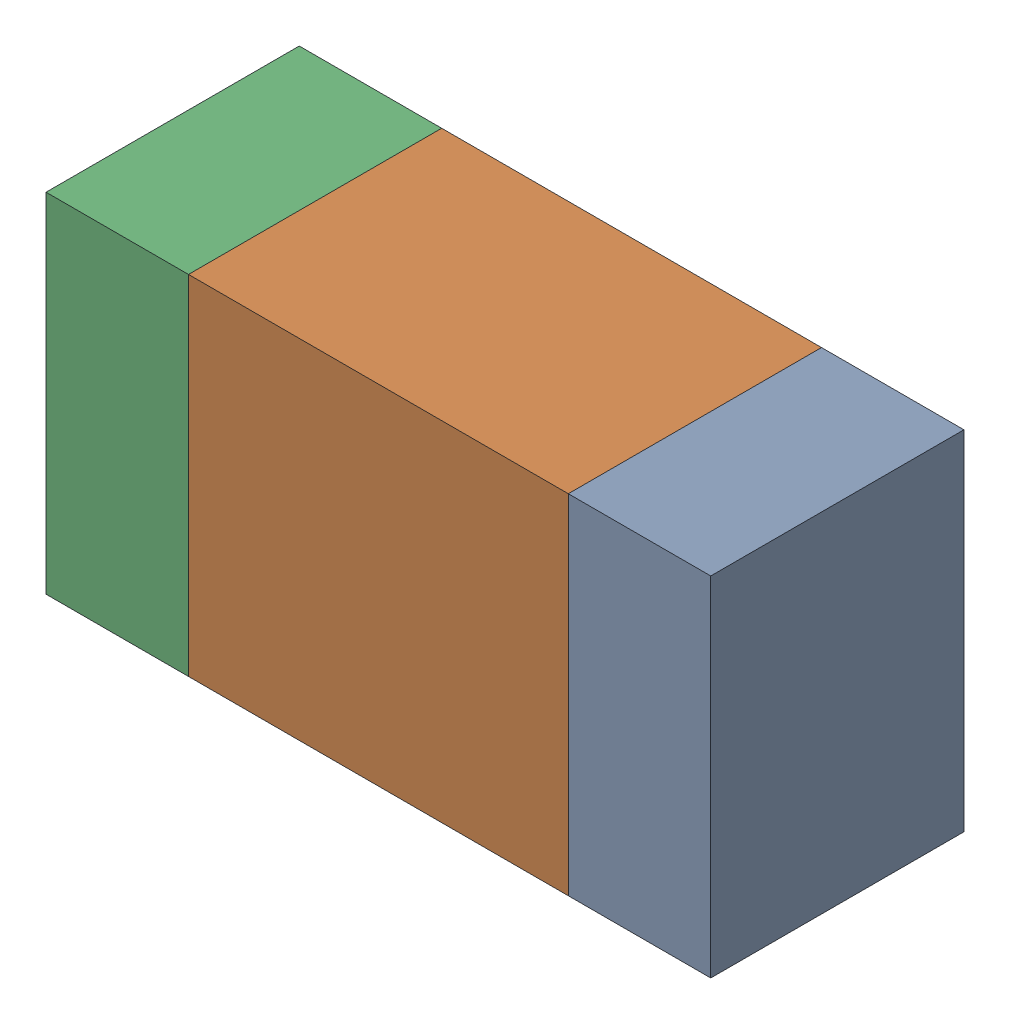
SolidWorks assembly R605_2PCB, configuration Default. Lengths in mm.
Overall size (1.05 0.55 0.4).
6 component instances, 2 part files, 0 mates.
Components (placement in the parent):
- 854785432-1: 854785432 [Default] at (101.5124 100.2001 -2.0638) size (0.22 0.55 0.4)
  - Extruded-1: Extruded [Default] at origin size (0.22 0.55 0.4)
- 854785568-1: 854785568 [Default] at (101.0999 100.2001 -2.0638) size (0.6 0.55 0.4)
  - Extruded_2-1: Extruded_2 [Default] at origin size (0.6 0.55 0.4)
- 854785432-2: 854785432 [Default] at (100.6874 100.2001 -2.0638) size (0.22 0.55 0.4)
  - Extruded-1: Extruded [Default] at origin size (0.22 0.55 0.4)
